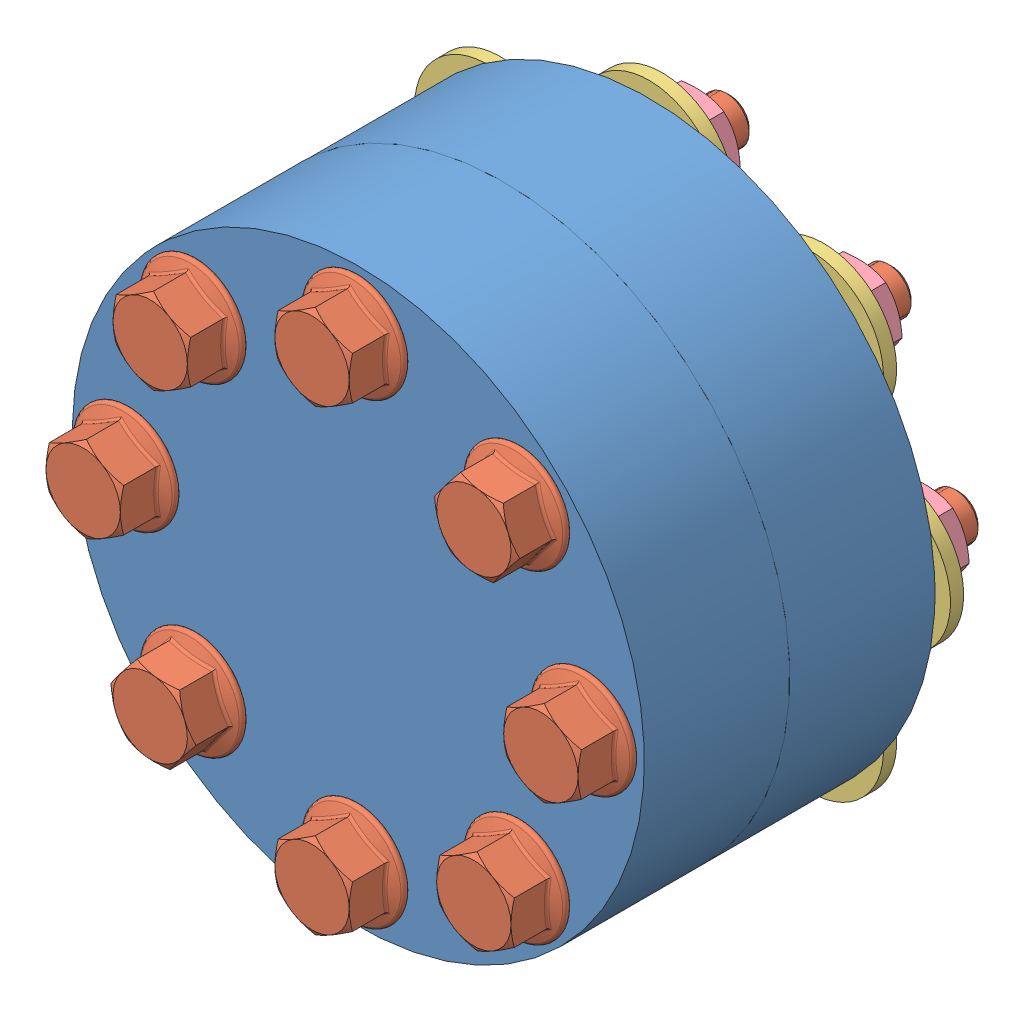
SolidWorks assembly Peça20 - Montagem, configuration Valor predeterminado. Lengths in mm.
Overall size (141.42 141.42 73.1).
26 component instances, 4 part files, 50 mates.
Components (placement in the parent):
- Peça20-1: Peça20 [Valor predeterminado] at (2.2869 29.0138 -12.7) size (100 100 25.4)
- Peça20-2: Peça20 [Valor predeterminado] at (2.2869 29.0138 12.7) x (-0.707107 0.707107 0) z (0 0 1) size (100 100 25.4)
- heavy hex flange screw_am-9: heavy hex flange screw_am [B18.2.3.9M - Heavy hex flange screw, M8 x 1.25 x 65 --22N] at (-37.7131 29.0138 46.2) x (0 0 -1) z (1 0 0) size (73.1 18 18)
- heavy hex flange screw_am-10: heavy hex flange screw_am [B18.2.3.9M - Heavy hex flange screw, M8 x 1.25 x 65 --22N] at (-25.9973 0.7295 46.2) x (0 0 -1) z (-0.923728 -0.383049 0) size (73.1 18 18)
- heavy hex flange screw_am-11: heavy hex flange screw_am [B18.2.3.9M - Heavy hex flange screw, M8 x 1.25 x 65 --22N] at (2.2869 -10.9862 46.2) x (0 0 -1) z (1 0 0) size (73.1 18 18)
- heavy hex flange screw_am-12: heavy hex flange screw_am [B18.2.3.9M - Heavy hex flange screw, M8 x 1.25 x 65 --22N] at (30.5712 0.7295 46.2) x (0 0 -1) z (1 0 0) size (73.1 18 18)
- heavy hex flange screw_am-13: heavy hex flange screw_am [B18.2.3.9M - Heavy hex flange screw, M8 x 1.25 x 65 --22N] at (42.2869 29.0138 46.2) x (0 0 -1) z (1 0 0) size (73.1 18 18)
- heavy hex flange screw_am-14: heavy hex flange screw_am [B18.2.3.9M - Heavy hex flange screw, M8 x 1.25 x 65 --22N] at (30.5712 57.298 46.2) x (0 0 -1) z (-0.923728 -0.383049 0) size (73.1 18 18)
- heavy hex flange screw_am-15: heavy hex flange screw_am [B18.2.3.9M - Heavy hex flange screw, M8 x 1.25 x 65 --22N] at (2.2869 69.0138 46.2) x (0 0 -1) z (1 0 0) size (73.1 18 18)
- heavy hex flange screw_am-16: heavy hex flange screw_am [B18.2.3.9M - Heavy hex flange screw, M8 x 1.25 x 65 --22N] at (-25.9973 57.298 46.2) x (0 0 -1) z (1 0 0) size (73.1 18 18)
- flat washer regular_am-1: flat washer regular_am [B18.22M - Plain washer, 8 mm, regular] at (2.2869 69.0138 -12.7) x (0 0 1) z (1 0 0) size (2.3 25.4 25.4)
- flat washer regular_am-2: flat washer regular_am [B18.22M - Plain washer, 8 mm, regular] at (-25.9973 57.298 -12.7) x (0 0 1) z (-1 0 0) size (2.3 25.4 25.4)
- flat washer regular_am-3: flat washer regular_am [B18.22M - Plain washer, 8 mm, regular] at (-37.7131 29.0138 -12.7) x (0 0 1) z (-1 0 0) size (2.3 25.4 25.4)
- flat washer regular_am-4: flat washer regular_am [B18.22M - Plain washer, 8 mm, regular] at (-25.9973 0.7295 -12.7) x (0 0 1) z (-1 0 0) size (2.3 25.4 25.4)
- flat washer regular_am-5: flat washer regular_am [B18.22M - Plain washer, 8 mm, regular] at (2.2869 -10.9862 -12.7) x (0 0 1) z (-1 0 0) size (2.3 25.4 25.4)
- flat washer regular_am-6: flat washer regular_am [B18.22M - Plain washer, 8 mm, regular] at (30.5712 0.7295 -12.7) x (0 0 1) z (-1 0 0) size (2.3 25.4 25.4)
- flat washer regular_am-7: flat washer regular_am [B18.22M - Plain washer, 8 mm, regular] at (42.2869 29.0138 -12.7) x (0 0 1) z (-1 0 0) size (2.3 25.4 25.4)
- flat washer regular_am-8: flat washer regular_am [B18.22M - Plain washer, 8 mm, regular] at (30.5712 57.298 -12.7) x (0 0 1) z (-1 0 0) size (2.3 25.4 25.4)
- hex nut style 1_am-1: hex nut style 1_am [B18.2.4.1M - Hex nut, Style 1,  M8 x 1.25 --D-N] at (-25.9973 57.298 -21.8) x (0.923728 0.383049 0) z (0 0 -1) size (13 15.01 6.8)
- hex nut style 1_am-2: hex nut style 1_am [B18.2.4.1M - Hex nut, Style 1,  M8 x 1.25 --D-N] at (-37.7131 29.0138 -21.8) x (0.923728 0.383049 0) z (0 0 -1) size (13 15.01 6.8)
- hex nut style 1_am-3: hex nut style 1_am [B18.2.4.1M - Hex nut, Style 1,  M8 x 1.25 --D-N] at (-25.9973 0.7295 -21.8) x (0.923728 0.383049 0) z (0 0 -1) size (13 15.01 6.8)
- hex nut style 1_am-4: hex nut style 1_am [B18.2.4.1M - Hex nut, Style 1,  M8 x 1.25 --D-N] at (2.2869 -10.9862 -21.8) x (0.923728 0.383049 0) z (0 0 -1) size (13 15.01 6.8)
- hex nut style 1_am-5: hex nut style 1_am [B18.2.4.1M - Hex nut, Style 1,  M8 x 1.25 --D-N] at (30.5712 0.7295 -21.8) x (0.923728 0.383049 0) z (0 0 -1) size (13 15.01 6.8)
- hex nut style 1_am-6: hex nut style 1_am [B18.2.4.1M - Hex nut, Style 1,  M8 x 1.25 --D-N] at (42.2869 29.0138 -21.8) x (0.923728 0.383049 0) z (0 0 -1) size (13 15.01 6.8)
- hex nut style 1_am-7: hex nut style 1_am [B18.2.4.1M - Hex nut, Style 1,  M8 x 1.25 --D-N] at (30.5712 57.298 -21.8) x (-0.923728 -0.383049 0) z (0 0 -1) size (13 15.01 6.8)
- hex nut style 1_am-8: hex nut style 1_am [B18.2.4.1M - Hex nut, Style 1,  M8 x 1.25 --D-N] at (2.2869 69.0138 -21.8) x (0.923728 0.383049 0) z (0 0 -1) size (13 15.01 6.8)
Mates (geometry in assembly coordinates):
- Coincidente1: coincident aligned: circle of Peça20-1; circle of Peça20-2
- Coincidente2: coincident aligned: circle of Peça20-1; circle of Peça20-2
- Concêntrico10: concentric anti-aligned: cylinder of Peça20-2 through (-37.7131 29.0138 38.1) axis (0 0 -1) radius 4; cylinder of heavy hex flange screw_am-9 through (-37.7131 29.0138 46.2) axis (0 0 1) radius 4
- Coincidente11: coincident anti-aligned: plane of Peça20-2 through (2.2869 29.0138 38.1) normal (0 0 1); plane of heavy hex flange screw_am-9 through (-37.7131 36.5193 38.1) normal (0 0 -1)
- Concêntrico11: concentric anti-aligned: cylinder of Peça20-2 through (-25.9973 0.7295 38.1) axis (0 0 -1) radius 4; cylinder of heavy hex flange screw_am-10 through (-25.9973 0.7295 46.2) axis (0 0 1) radius 4
- Coincidente12: coincident anti-aligned: plane of Peça20-2 through (2.2869 29.0138 38.1) normal (0 0 1); plane of heavy hex flange screw_am-10 through (-23.1223 -6.2036 38.1) normal (0 0 -1)
- Concêntrico12: concentric anti-aligned: cylinder of Peça20-2 through (2.2869 -10.9862 38.1) axis (0 0 -1) radius 4; cylinder of heavy hex flange screw_am-11 through (2.2869 -10.9862 46.2) axis (0 0 1) radius 4
- Coincidente13: coincident anti-aligned: plane of Peça20-2 through (2.2869 29.0138 38.1) normal (0 0 1); plane of heavy hex flange screw_am-11 through (2.2869 -3.4807 38.1) normal (0 0 -1)
- Concêntrico13: concentric anti-aligned: cylinder of Peça20-2 through (30.5712 0.7295 38.1) axis (0 0 -1) radius 4; cylinder of heavy hex flange screw_am-12 through (30.5712 0.7295 46.2) axis (0 0 1) radius 4
- Coincidente14: coincident anti-aligned: plane of Peça20-2 through (2.2869 29.0138 38.1) normal (0 0 1); plane of heavy hex flange screw_am-12 through (30.5712 8.235 38.1) normal (0 0 -1)
- Concêntrico14: concentric anti-aligned: cylinder of Peça20-2 through (42.2869 29.0138 38.1) axis (0 0 -1) radius 4; cylinder of heavy hex flange screw_am-13 through (42.2869 29.0138 46.2) axis (0 0 1) radius 4
- Coincidente15: coincident anti-aligned: plane of Peça20-2 through (2.2869 29.0138 38.1) normal (0 0 1); plane of heavy hex flange screw_am-13 through (42.2869 36.5193 38.1) normal (0 0 -1)
- Concêntrico15: concentric anti-aligned: cylinder of Peça20-2 through (30.5712 57.298 38.1) axis (0 0 -1) radius 4; cylinder of heavy hex flange screw_am-14 through (30.5712 57.298 46.2) axis (0 0 1) radius 4
- Coincidente16: coincident anti-aligned: plane of Peça20-2 through (2.2869 29.0138 38.1) normal (0 0 1); plane of heavy hex flange screw_am-14 through (33.4462 50.3649 38.1) normal (0 0 -1)
- Concêntrico16: concentric anti-aligned: cylinder of Peça20-2 through (2.2869 69.0138 38.1) axis (0 0 -1) radius 4; cylinder of heavy hex flange screw_am-15 through (2.2869 69.0138 46.2) axis (0 0 1) radius 4
- Coincidente17: coincident anti-aligned: plane of Peça20-2 through (2.2869 29.0138 38.1) normal (0 0 1); plane of heavy hex flange screw_am-15 through (2.2869 76.5193 38.1) normal (0 0 -1)
- Concêntrico17: concentric anti-aligned: cylinder of Peça20-2 through (-25.9973 57.298 38.1) axis (0 0 -1) radius 4; cylinder of heavy hex flange screw_am-16 through (-25.9973 57.298 46.2) axis (0 0 1) radius 4
- Coincidente18: coincident anti-aligned: plane of Peça20-2 through (2.2869 29.0138 38.1) normal (0 0 1); plane of heavy hex flange screw_am-16 through (-25.9973 64.8036 38.1) normal (0 0 -1)
- Concêntrico18: concentric anti-aligned: cylinder of heavy hex flange screw_am-15 through (2.2869 69.0138 46.2) axis (0 0 1) radius 4; cylinder of flat washer regular_am-1 through (2.2869 69.0138 -47.625) axis (0 0 -1) radius 4.56
- Coincidente19: coincident anti-aligned: plane of Peça20-1 through (2.2869 29.0138 -12.7) normal (0 0 -1); plane of flat washer regular_am-1 through (2.2869 64.4538 -12.7) normal (0 0 1)
- Concêntrico19: concentric anti-aligned: cylinder of heavy hex flange screw_am-16 through (-25.9973 57.298 46.2) axis (0 0 1) radius 4; cylinder of flat washer regular_am-2 through (-25.9973 57.298 -47.625) axis (0 0 -1) radius 4.56
- Coincidente20: coincident anti-aligned: plane of Peça20-1 through (2.2869 29.0138 -12.7) normal (0 0 -1); plane of flat washer regular_am-2 through (-25.9973 61.858 -12.7) normal (0 0 1)
- Concêntrico20: concentric anti-aligned: cylinder of heavy hex flange screw_am-9 through (-37.7131 29.0138 46.2) axis (0 0 1) radius 4; cylinder of flat washer regular_am-3 through (-37.7131 29.0138 -47.625) axis (0 0 -1) radius 4.56
- Coincidente21: coincident anti-aligned: plane of Peça20-1 through (2.2869 29.0138 -12.7) normal (0 0 -1); plane of flat washer regular_am-3 through (-37.7131 33.5738 -12.7) normal (0 0 1)
- Concêntrico21: concentric anti-aligned: cylinder of heavy hex flange screw_am-10 through (-25.9973 0.7295 46.2) axis (0 0 1) radius 4; cylinder of flat washer regular_am-4 through (-25.9973 0.7295 -47.625) axis (0 0 -1) radius 4.56
- Coincidente22: coincident anti-aligned: plane of Peça20-1 through (2.2869 29.0138 -12.7) normal (0 0 -1); plane of flat washer regular_am-4 through (-25.9973 5.2895 -12.7) normal (0 0 1)
- Concêntrico22: concentric anti-aligned: cylinder of heavy hex flange screw_am-11 through (2.2869 -10.9862 46.2) axis (0 0 1) radius 4; cylinder of flat washer regular_am-5 through (2.2869 -10.9862 -47.625) axis (0 0 -1) radius 4.56
- Coincidente23: coincident anti-aligned: plane of Peça20-1 through (2.2869 29.0138 -12.7) normal (0 0 -1); plane of flat washer regular_am-5 through (2.2869 -6.4262 -12.7) normal (0 0 1)
- Concêntrico23: concentric anti-aligned: cylinder of heavy hex flange screw_am-12 through (30.5712 0.7295 46.2) axis (0 0 1) radius 4; cylinder of flat washer regular_am-6 through (30.5712 0.7295 -47.625) axis (0 0 -1) radius 4.56
- Coincidente24: coincident anti-aligned: plane of Peça20-1 through (2.2869 29.0138 -12.7) normal (0 0 -1); plane of flat washer regular_am-6 through (30.5712 5.2895 -12.7) normal (0 0 1)
- Concêntrico24: concentric anti-aligned: cylinder of heavy hex flange screw_am-13 through (42.2869 29.0138 46.2) axis (0 0 1) radius 4; cylinder of flat washer regular_am-7 through (42.2869 29.0138 -47.625) axis (0 0 -1) radius 4.56
- Coincidente25: coincident anti-aligned: plane of Peça20-1 through (2.2869 29.0138 -12.7) normal (0 0 -1); plane of flat washer regular_am-7 through (42.2869 33.5738 -12.7) normal (0 0 1)
- Concêntrico25: concentric anti-aligned: cylinder of heavy hex flange screw_am-14 through (30.5712 57.298 46.2) axis (0 0 1) radius 4; cylinder of flat washer regular_am-8 through (30.5712 57.298 -47.625) axis (0 0 -1) radius 4.56
- Coincidente26: coincident anti-aligned: plane of Peça20-1 through (2.2869 29.0138 -12.7) normal (0 0 -1); plane of flat washer regular_am-8 through (30.5712 61.858 -12.7) normal (0 0 1)
- Concêntrico34: concentric anti-aligned: cylinder of heavy hex flange screw_am-16 through (-25.9973 57.298 46.2) axis (0 0 1) radius 4; cylinder of hex nut style 1_am-1 through (-25.9973 57.298 3.2375) axis (0 0 -1) radius 4
- Coincidente36: coincident anti-aligned: plane of flat washer regular_am-2 through (-25.9973 69.998 -15) normal (0 0 -1); plane of hex nut style 1_am-1 through (-23.1223 50.3649 -15) normal (0 0 1)
- Concêntrico35: concentric anti-aligned: cylinder of heavy hex flange screw_am-9 through (-37.7131 29.0138 46.2) axis (0 0 1) radius 4; cylinder of hex nut style 1_am-2 through (-37.7131 29.0138 3.2375) axis (0 0 -1) radius 4
- Coincidente37: coincident anti-aligned: plane of flat washer regular_am-3 through (-37.7131 41.7138 -15) normal (0 0 -1); plane of hex nut style 1_am-2 through (-34.8381 22.0807 -15) normal (0 0 1)
- Concêntrico36: concentric anti-aligned: cylinder of heavy hex flange screw_am-10 through (-25.9973 0.7295 46.2) axis (0 0 1) radius 4; cylinder of hex nut style 1_am-3 through (-25.9973 0.7295 3.2375) axis (0 0 -1) radius 4
- Coincidente38: coincident anti-aligned: plane of flat washer regular_am-4 through (-25.9973 13.4295 -15) normal (0 0 -1); plane of hex nut style 1_am-3 through (-23.1223 -6.2036 -15) normal (0 0 1)
- Concêntrico37: concentric anti-aligned: cylinder of heavy hex flange screw_am-11 through (2.2869 -10.9862 46.2) axis (0 0 1) radius 4; cylinder of hex nut style 1_am-4 through (2.2869 -10.9862 3.2375) axis (0 0 -1) radius 4
- Coincidente39: coincident anti-aligned: plane of flat washer regular_am-5 through (2.2869 1.7138 -15) normal (0 0 -1); plane of hex nut style 1_am-4 through (5.1619 -17.9193 -15) normal (0 0 1)
- Concêntrico38: concentric anti-aligned: cylinder of heavy hex flange screw_am-12 through (30.5712 0.7295 46.2) axis (0 0 1) radius 4; cylinder of hex nut style 1_am-5 through (30.5712 0.7295 3.2375) axis (0 0 -1) radius 4
- Coincidente40: coincident anti-aligned: plane of flat washer regular_am-6 through (30.5712 13.4295 -15) normal (0 0 -1); plane of hex nut style 1_am-5 through (33.4462 -6.2036 -15) normal (0 0 1)
- Concêntrico39: concentric anti-aligned: cylinder of heavy hex flange screw_am-13 through (42.2869 29.0138 46.2) axis (0 0 1) radius 4; cylinder of hex nut style 1_am-6 through (42.2869 29.0138 3.2375) axis (0 0 -1) radius 4
- Coincidente41: coincident anti-aligned: plane of flat washer regular_am-7 through (42.2869 41.7138 -15) normal (0 0 -1); plane of hex nut style 1_am-6 through (45.1619 22.0807 -15) normal (0 0 1)
- Concêntrico40: concentric anti-aligned: cylinder of heavy hex flange screw_am-14 through (30.5712 57.298 46.2) axis (0 0 1) radius 4; cylinder of hex nut style 1_am-7 through (30.5712 57.298 3.2375) axis (0 0 -1) radius 4
- Coincidente42: coincident anti-aligned: plane of flat washer regular_am-8 through (30.5712 69.998 -15) normal (0 0 -1); plane of hex nut style 1_am-7 through (27.6962 64.2311 -15) normal (0 0 1)
- Concêntrico41: concentric anti-aligned: cylinder of heavy hex flange screw_am-15 through (2.2869 69.0138 46.2) axis (0 0 1) radius 4; cylinder of hex nut style 1_am-8 through (2.2869 69.0138 3.2375) axis (0 0 -1) radius 4
- Coincidente43: coincident anti-aligned: plane of flat washer regular_am-1 through (2.2869 56.3138 -15) normal (0 0 -1); plane of hex nut style 1_am-8 through (5.1619 62.0807 -15) normal (0 0 1)
